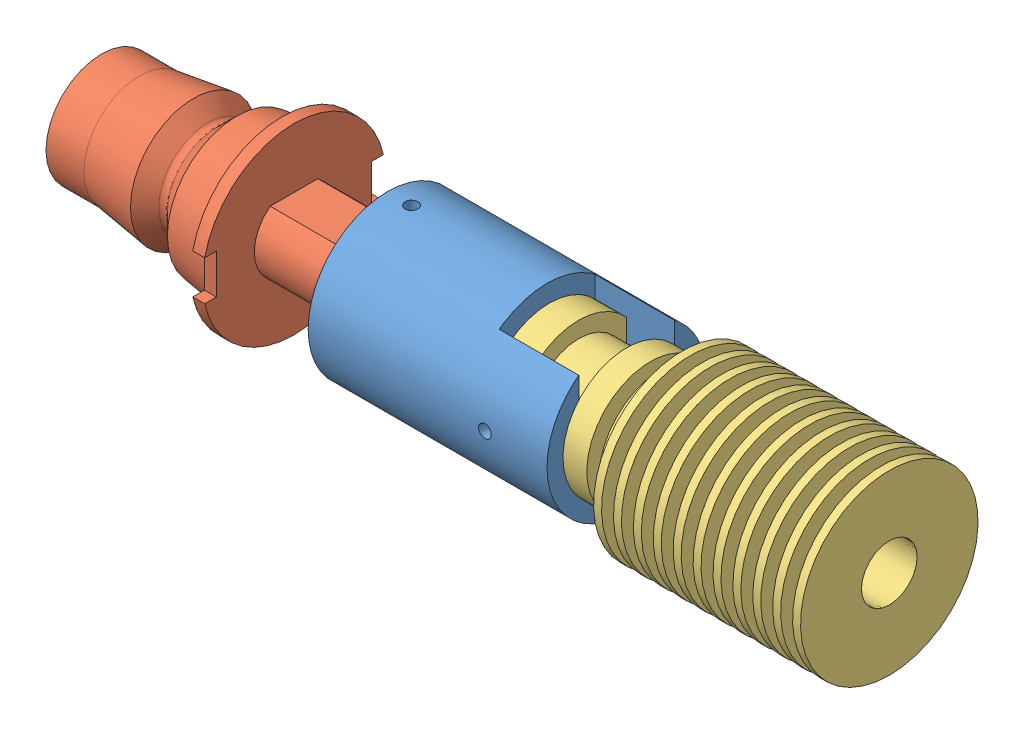
SolidWorks assembly Assem1, configuration Default. Lengths in mm.
Overall size (98.95 23 22.45).
3 component instances, 3 part files, 5 mates.
Components (placement in the parent):
- adapter-1: adapter [Default] at (-145.5731 17.8613 53.9473) size (30 20 20)
- ER11 tool holder butt-1: ER11 tool holder butt [Default] at (-181.5227 17.8613 53.9473) size (44.18 23 22.45)
- heatsink-1: heatsink [Default] at (-125.2731 17.8613 53.9473) size (42.7 22.3 22.3)
Mates (geometry in assembly coordinates):
- Concentric1: concentric anti-aligned: circle of adapter-1; circle of ER11 tool holder butt-1
- Perpendicular1: perpendicular: plane of ER11 tool holder butt-1 through (-137.3462 21.8613 56.9473) normal (0 1 0); line of assembly
- Perpendicular2: perpendicular: plane of heatsink-1 through (-82.5721 23.1528 59.9473) normal (0 0 1); line of assembly
- Concentric2: concentric anti-aligned: circle of adapter-1; circle of heatsink-1
- Coincident4: coincident anti-aligned: plane of adapter-1 through (-115.5731 17.8613 53.9473) normal (1 0 0); plane of heatsink-1 through (-115.5731 9.8613 53.9473) normal (-1 0 0)
